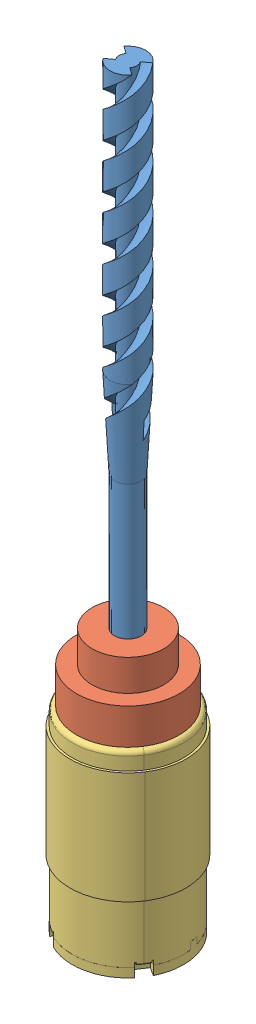
SolidWorks assembly drill, configuration Default. Lengths in mm.
Overall size (36.61 176.85 36.4).
3 component instances, 3 part files, 4 mates.
Components (placement in the parent):
- DRILL-1: DRILL [Default] at (-13.3618 16.1001 -28.7594) size (8.45 114.43 8.38)
- Drill connect-1: Drill connect [Default] at (-13.3618 223.5996 -28.7594) size (22.92 15 22.92)
- Medium motor-1: Medium motor [Default] at (-29.6887 221.7857 -28.4817) x (-0.832298 0.008789 -0.554259) z (0.007315 0.999961 0.004871) size (26.16 25.94 63.52)
Mates (geometry in assembly coordinates):
- Concentric1: concentric: circle of DRILL-1; circle of Drill connect-1
- Coincident2: coincident: circle of DRILL-1; circle of Drill connect-1
- Concentric2: concentric: circle of Drill connect-1; circle of Medium motor-1
- Coincident3: coincident: plane of Drill connect-1 through (-13.3618 223.5996 -28.7594) normal (0 -1 0); plane of Medium motor-1 through (-13.3618 223.5996 -28.7594) normal (0 1 0)
